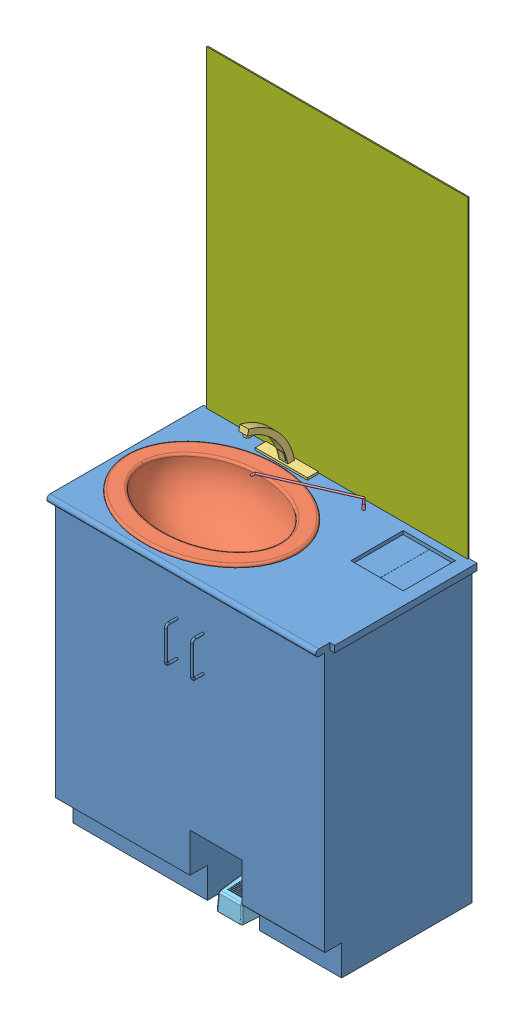
SolidWorks assembly Final_Sink_Assembly, configuration Detailed. Lengths in mm.
Overall size (784.36 1779.52 466.72).
7 component instances, 7 part files, 16 mates.
Components (placement in the parent):
- Sink_Cabinet_Indiv-1: Sink_Cabinet_Indiv [Detailed] at (-19.1349 100.1549 1083.236) size (784.35 865.12 466.73)
- Sink Regular-1: Sink Regular [Default] at (260.2651 972.8989 867.336) size (530.37 175.34 425.63)
- Faucet_indiv-1: Faucet_indiv [Default] at (336.4651 965.2789 632.386) x (-1 0 0) z (0 0 -1) size (152.4 151.35 143.5)
- Soap Pump Head-1: Soap Pump Head [Default] at (492.966 965.2789 656.2861) x (0.707504 0 0.706709) z (-0.706709 0 0.707504) size (7 94.57 237.72)
- Soap Foot Pump-1: Soap Foot Pump [Default] at (426.3151 100.1549 1019.736) size (89.29 56.68 113.79)
- Cabinet_garb-1: Cabinet_garb [Default] at (544.4911 385.5799 1032.436) size (228.6 304.8 381)
- Mirror-1: Mirror [Default] at (-19.1349 100.1549 626.036) x (-1 0 0) z (0 0 -1) size (762 914.4 3.3)
Mates (geometry in assembly coordinates):
- Coincident3: coincident aligned: plane of Sink_Cabinet_Indiv-1 through (-19.1349 965.2789 1083.236) normal (0 1 0); plane of Sink Regular-1 through (260.2651 965.2789 867.336) normal (0 1 0)
- Coincident4: coincident anti-aligned: line of Sink_Cabinet_Indiv-1 through (260.2651 950.8899 867.336) axis (0 1 0); line of Sink Regular-1 through (260.2651 1273.2031 867.336) axis (0 -1 0)
- Coincident5: coincident anti-aligned: plane of Sink_Cabinet_Indiv-1 through (-19.1349 965.2789 1083.236) normal (0 1 0); plane of Faucet_indiv-1 through (336.4651 965.2789 632.386) normal (0 -1 0)
- Distance2: distance = 6.35 mm: line of Faucet_indiv-1 through (336.4651 965.2789 632.386) axis (-1 0 0); line of Sink_Cabinet_Indiv-1 through (779.4411 965.2789 626.036) axis (-1 0 0)
- Coincident8: coincident anti-aligned: plane of Sink_Cabinet_Indiv-1 through (-19.1349 965.2789 1083.236) normal (0 1 0); circle of Soap Pump Head-1
- Coincident11: coincident anti-aligned: plane of Sink_Cabinet_Indiv-1 through (773.0911 201.7549 -411.572) normal (-1 0 0); plane of Cabinet_garb-1 through (773.0911 690.3799 1032.436) normal (1 0 0)
- Coincident12: coincident anti-aligned: plane of Sink_Cabinet_Indiv-1 through (-19.1349 965.2789 651.436) normal (0 0 1); plane of Cabinet_garb-1 through (544.4911 690.3799 651.436) normal (0 0 -1)
- Coincident13: coincident aligned: plane of Sink_Cabinet_Indiv-1 through (-19.1349 100.1549 1083.236) normal (0 1 0); plane of Soap Foot Pump-1 through (426.3151 100.1549 1019.736) normal (0 1 0)
- Parallel1: parallel aligned: plane of Soap Foot Pump-1 through (426.3151 100.1549 1019.736) normal (1 0 0)
- Coincident15: coincident aligned: line of Sink_Cabinet_Indiv-1 through (463.4651 100.1549 880.036) axis (0 0 1); line of Soap Foot Pump-1 through (463.4651 100.1549 905.9461) axis (0 0 1)
- Distance4: distance = 12.7 mm: line of Soap Foot Pump-1 through (426.3151 100.1549 1019.736) axis (1 0 0); line of Sink_Cabinet_Indiv-1 through (539.6651 100.1549 1007.036) axis (1 0 0)
- Coincident17: coincident: line of Sink_Cabinet_Indiv-1 through (260.2651 965.2789 705.284) axis (0 0 1); plane of Faucet_indiv-1 through (260.2651 965.2789 632.386) normal (-1 0 0)
- InPlace1: in place: plane of Sink_Cabinet_Indiv-1 through (-19.1349 100.1549 626.036) normal (0 0 -1); plane of Mirror-1 through (-19.1349 100.1549 626.036) normal (0 0 -1); moOrthogonalPlaneRef_w of Sink_Cabinet_Indiv-1 through (-19.1349 100.1549 626.036) normal (0 0 -1); plane of Mirror-1 through (-19.1349 100.1549 626.036) normal (0 1 0); plane of Sink_Cabinet_Indiv-1 through (-19.1349 100.1549 626.036) normal (0 0 -1); plane of Mirror-1 through (-19.1349 100.1549 626.036) normal (-1 0 0); plane of Sink_Cabinet_Indiv-1 through (-19.1349 100.1549 626.036) normal (0 0 -1); unknown of Mirror-1
- Coincident18: coincident aligned: plane of Sink_Cabinet_Indiv-1; plane of Mirror-1
- Coincident19: coincident aligned: moOrthogonalPlaneRef_w of Sink_Cabinet_Indiv-1; plane of Part1^Final_Sink_Assembly-1 through (-19.1349 100.1549 626.036) normal (0 1 0)
- Coincident20: coincident anti-aligned: moOrthogonalPlaneRef_w of Sink_Cabinet_Indiv-1; plane of Part1^Final_Sink_Assembly-1 through (-19.1349 100.1549 626.036) normal (-1 0 0)
